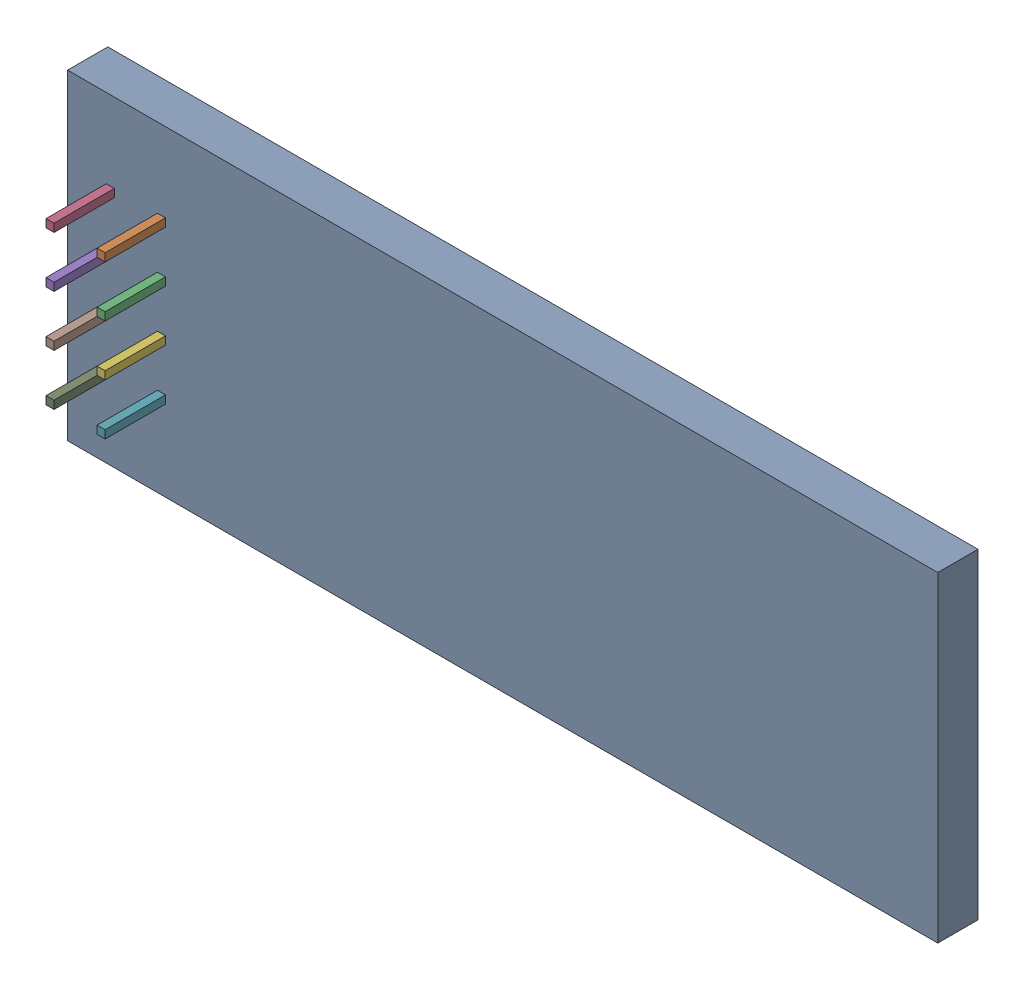
SolidWorks assembly U3-2, configuration Default. Lengths in mm.
Overall size (43.25 15.95 5.5).
18 component instances, 2 part files, 0 mates.
Components (placement in the parent):
- 959206080-2-1: 959206080-2 [Default] at (102.177 84.441 -2.3912) size (43.25 15.95 2)
  - Extruded-68-1: Extruded-68 [Default] at origin size (43.25 15.95 2)
- 959205944-2-1: 959205944-2 [Default] at (85.217 88.291 -2.8912) size (0.4 0.4 5.5)
  - Extruded-69-1: Extruded-69 [Default] at origin size (0.4 0.4 5.5)
- 959205944-2-2: 959205944-2 [Default] at (85.217 85.751 -2.8912) size (0.4 0.4 5.5)
  - Extruded-69-1: Extruded-69 [Default] at origin size (0.4 0.4 5.5)
- 959205944-2-3: 959205944-2 [Default] at (82.677 88.291 -2.8912) size (0.4 0.4 5.5)
  - Extruded-69-1: Extruded-69 [Default] at origin size (0.4 0.4 5.5)
- 959205944-2-4: 959205944-2 [Default] at (82.677 85.751 -2.8912) size (0.4 0.4 5.5)
  - Extruded-69-1: Extruded-69 [Default] at origin size (0.4 0.4 5.5)
- 959205944-2-5: 959205944-2 [Default] at (85.217 83.211 -2.8912) size (0.4 0.4 5.5)
  - Extruded-69-1: Extruded-69 [Default] at origin size (0.4 0.4 5.5)
- 959205944-2-6: 959205944-2 [Default] at (85.217 80.671 -2.8912) size (0.4 0.4 5.5)
  - Extruded-69-1: Extruded-69 [Default] at origin size (0.4 0.4 5.5)
- 959205944-2-7: 959205944-2 [Default] at (82.677 83.211 -2.8912) size (0.4 0.4 5.5)
  - Extruded-69-1: Extruded-69 [Default] at origin size (0.4 0.4 5.5)
- 959205944-2-8: 959205944-2 [Default] at (82.677 80.671 -2.8912) size (0.4 0.4 5.5)
  - Extruded-69-1: Extruded-69 [Default] at origin size (0.4 0.4 5.5)
